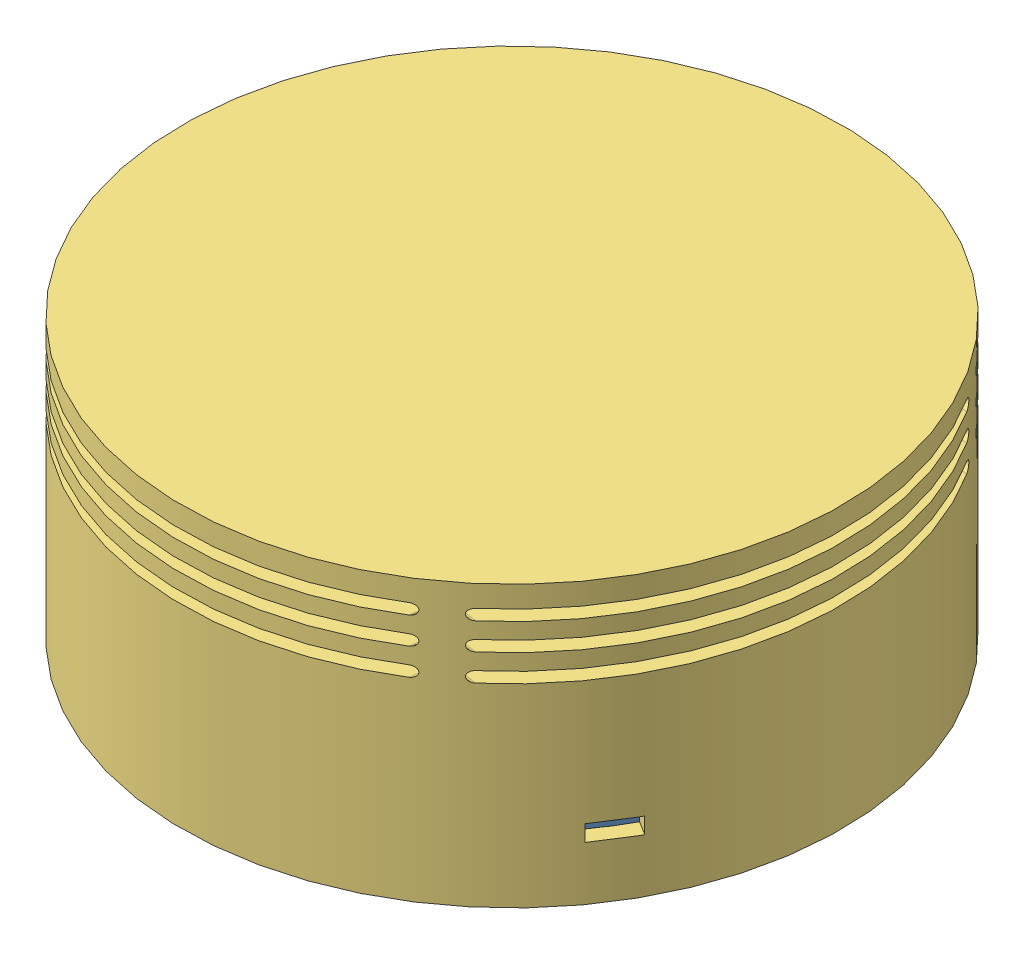
SolidWorks assembly Gehaeuse_Wetterstation, configuration Standard. Lengths in mm.
Overall size (139.27 52 139.27).
4 component instances, 4 part files, 9 mates.
Components (placement in the parent):
- Aufnahme_Boden-1: Aufnahme_Boden [Standard] at (0.2189 -11.2585 106.4092) size (116.31 20 116.31)
- SDS011-1: SDS011 [Standard] at (-0.3435 15.7415 103.3876) x (0.533076 0 -0.846068) z (0.846068 0 0.533076) size (70 25.5 71.26)
- Aufnahme_Deckel-1: Aufnahme_Deckel [Standard] at (0.2189 -11.2585 106.4092) x (0.988687 0 0.149995) z (-0.149995 0 0.988687) size (122.31 52 122.31)
- ConnectorBoard v1-1: ConnectorBoard v1 [Standard] at (52.1123 12.2415 94.231) x (-0.533076 0 0.846068) z (0 -1 0) size (70.59 71.77 11.84)
Mates (geometry in assembly coordinates):
- Deckungsgleich11: coincident anti-aligned: line of Aufnahme_Boden-1 through (13.8041 -4.6001 49.8639) axis (0 1 0); line of Aufnahme_Deckel-1 through (13.8041 0.3081 49.8639) axis (0 -1 0)
- Konzentrisch8: concentric aligned: cylinder of Aufnahme_Boden-1 through (0.2189 8.7415 106.4092) axis (0 -1 0) radius 58.1543; cylinder of Aufnahme_Deckel-1 through (0.2189 38.7415 106.4092) axis (0 -1 0) radius 58.1543
- Deckungsgleich14: coincident aligned: plane of Aufnahme_Boden-1 through (0.2189 -11.2585 106.4092) normal (0 -1 0); plane of Aufnahme_Deckel-1 through (0.2189 -11.2585 106.4092) normal (0 -1 0)
- Deckungsgleich16: coincident anti-aligned: plane of SDS011-1 through (-0.3435 17.7415 103.3876) normal (0 1 0); plane of Aufnahme_Deckel-1 through (22.6861 17.7415 124.9893) normal (0 -1 0)
- Konzentrisch10: concentric aligned: circle of SDS011-1; cylinder of Aufnahme_Deckel-1 through (22.6861 17.7415 124.9893) axis (0 1 0) radius 1.5
- Konzentrisch11: concentric anti-aligned: circle of SDS011-1; circle of Aufnahme_Deckel-1
- Konzentrisch12: concentric anti-aligned: circle of SDS011-1; circle of ConnectorBoard v1-1
- Deckungsgleich19: coincident anti-aligned: plane of SDS011-1 through (-0.3435 12.2415 103.3876) normal (0 -1 0); plane of ConnectorBoard v1-1 through (3.5115 12.2415 105.3271) normal (0 1 0)
- Parallel1: parallel anti-aligned: plane of SDS011-1 through (-0.3435 15.7415 103.3876) normal (0.846068 0 0.533076); plane of ConnectorBoard v1-1 through (52.1123 12.2415 94.231) normal (-0.846068 0 -0.533076)
